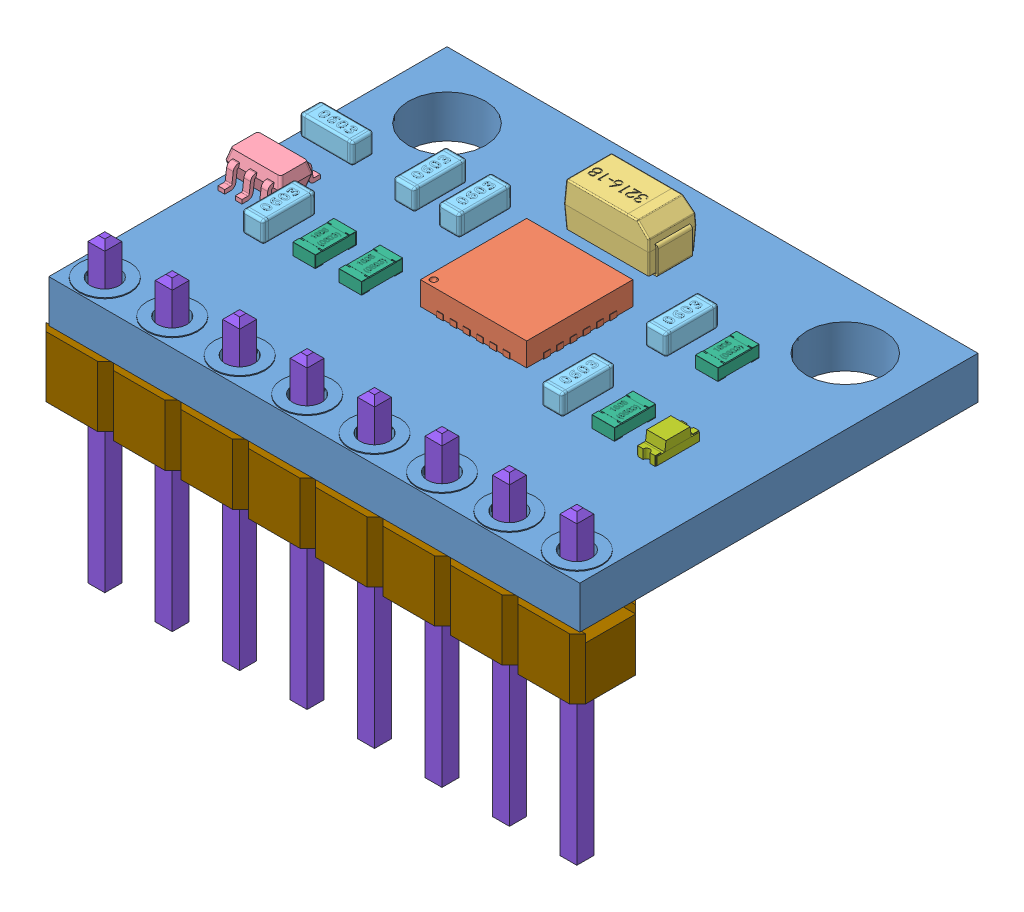
SolidWorks assembly User Library-GY-521, configuration Valor predeterminado. Lengths in mm.
Overall size (20.32 11.82 15.24).
18 component instances, 9 part files, 44 mates.
Components (placement in the parent):
- User Library-GY-521_placa-1: User Library-GY-521_placa [Valor predeterminado] at (0.5666 -1.5108 20) size (20 1.67 15)
- User Library-GY-521_User Library-mpu-6050_qfn-24-1: User Library-GY-521_User Library-mpu-6050_qfn-24 [Default] at (-1.4334 0.1092 17.5) x (0 0 1) z (-1 0 0) size (4.04 0.9 4.04)
- User Library-GY-521_User Library-CAP_TANT_3216-18_A_case-1-1: User Library-GY-521_User Library-CAP_TANT_3216-18_A_case-1 [Default] at (0.3666 0.0692 15.4) x (-1 0 0) z (0 0 -1) size (3.4 1.7 1.8)
- User Library-GY-521_User Library-sot353-1: User Library-GY-521_User Library-sot353 [По умолчанию] at (-8.2834 0.0892 20.35) x (-1 0 0) z (0 1 0) size (2.1 2.3 1)
- User Library-GY-521_User Library-0603(1608M) Cap-1: User Library-GY-521_User Library-0603(1608M) Cap [Default] at (4.4603 0.0892 17.5499) x (0 0 -1) z (1 0 0) size (2.01 0.8 0.79)
- User Library-GY-521_User Library-0603(1608M) Cap-2: User Library-GY-521_User Library-0603(1608M) Cap [Default] at (4.4603 0.0892 21.4501) x (0 0 -1) z (1 0 0) size (2.01 0.8 0.79)
- User Library-GY-521_User Library-RESC1608X05N-1: User Library-GY-521_User Library-RESC1608X05N [Default] at (6.174 0.0892 17.5499) x (0 0 -1) z (0 1 0) size (1.55 0.85 0.45)
- User Library-GY-521_User Library-RESC1608X05N-2: User Library-GY-521_User Library-RESC1608X05N [Default] at (6.174 0.0892 21.4501) x (0 0 -1) z (0 1 0) size (1.55 0.85 0.45)
- User Library-GY-521_User Library-LED SMD0603-1: User Library-GY-521_User Library-LED SMD0603 [Default] at (7.8618 0.0844 20.8327) x (1 0 0) z (0 1 0) size (0.73 1.65 0.68)
- User Library-GY-521_User Library-RESC1608X05N-3: User Library-GY-521_User Library-RESC1608X05N [Default] at (-3.3534 0.0892 21.4501) x (0 0 -1) z (0 1 0) size (1.55 0.85 0.45)
- User Library-GY-521_User Library-RESC1608X05N-4: User Library-GY-521_User Library-RESC1608X05N [Default] at (-5.0934 0.0892 21.4501) x (0 0 -1) z (0 1 0) size (1.55 0.85 0.45)
- User Library-GY-521_User Library-0603(1608M) Cap-3: User Library-GY-521_User Library-0603(1608M) Cap [Default] at (-6.8071 0.0892 21.4501) x (0 0 -1) z (1 0 0) size (2.01 0.8 0.79)
- User Library-GY-521_User Library-0603(1608M) Cap-4: User Library-GY-521_User Library-0603(1608M) Cap [Default] at (-8.2834 0.0892 17.8063) size (2.01 0.8 0.79)
- User Library-GY-521_User Library-0603(1608M) Cap-5: User Library-GY-521_User Library-0603(1608M) Cap [Default] at (-5.0145 0.0892 17.5499) x (0 0 -1) z (1 0 0) size (2.01 0.8 0.79)
- User Library-GY-521_User Library-0603(1608M) Cap-6: User Library-GY-521_User Library-0603(1608M) Cap [Default] at (-3.3271 0.0892 17.5499) x (0 0 -1) z (1 0 0) size (2.01 0.8 0.79)
- User Library-GY-521_User Library-Header_Male_8Pin-1: User Library-GY-521_User Library-Header_Male_8Pin [Default] at (-8.3234 -1.5108 26.5) x (1 0 0) z (0 -1 0) size (20.32 2.49 11.54)
  - User Library-GY-521_User Library-Header_Male_8Pin_PinArray-1: User Library-GY-521_User Library-Header_Male_8Pin_PinArray [Default] at origin size (18.42 0.64 11.54)
  - User Library-GY-521_User Library-Header_Male_8Pin_BodyArray-1: User Library-GY-521_User Library-Header_Male_8Pin_BodyArray [Default] at origin size (20.32 2.49 2.29)
Mates (geometry in assembly coordinates):
- Coincidente2: coincident anti-aligned: plane of User Library-GY-521_placa-1 through (0.5666 0.0892 20) normal (0 1 0); plane of User Library-GY-521_User Library-mpu-6050_qfn-24-1 through (2.6674 0.0892 17.3992) normal (0 -1 0)
- Distância1: distance = 6 mm aligned: plane of User Library-GY-521_User Library-mpu-6050_qfn-24-1 through (-1.5134 0.0916 21.5) normal (0 0 1); plane of User Library-GY-521_placa-1 through (-9.4334 0.0892 27.5) normal (0 0 1)
- Largura1: width anti-aligned: plane of User Library-GY-521_User Library-mpu-6050_qfn-24-1 through (2.5666 0.0916 21.58) normal (1 0 0); plane of User Library-GY-521_placa-1 through (-1.4334 0.0916 17.42) normal (-1 0 0); plane of User Library-GY-521_User Library-mpu-6050_qfn-24-1 through (-9.4334 0.0892 12.5) normal (-1 0 0); plane of User Library-GY-521_placa-1 through (10.5666 0.0892 12.5) normal (1 0 0)
- Coincidente4: coincident anti-aligned: plane of User Library-GY-521_placa-1 through (0.5666 0.0892 20) normal (0 1 0); plane of User Library-GY-521_User Library-CAP_TANT_3216-18_A_case-1-1 through (0.9166 0.0892 14.75) normal (0 -1 0)
- Distância2: distance = 8.5 mm aligned: plane of User Library-GY-521_User Library-CAP_TANT_3216-18_A_case-1-1 through (2.0666 0.1892 14.75) normal (1 0 0); plane of User Library-GY-521_placa-1 through (10.5666 0.0892 12.5) normal (1 0 0)
- Coincidente9: coincident anti-aligned: plane of User Library-GY-521_placa-1 through (0.5666 0.0892 20) normal (0 1 0); plane of User Library-GY-521_User Library-sot353-1 through (-8.1584 0.0892 21.5) normal (0 -1 0)
- Distância5: distance = 6.7 mm aligned: plane of User Library-GY-521_User Library-sot353-1 through (-7.5084 -1.5589 19.2) normal (0 0 -1); plane of User Library-GY-521_placa-1 through (-9.4334 0.0892 12.5) normal (0 0 -1)
- Distância6: distance = 0.1 mm: line of User Library-GY-521_User Library-sot353-1 through (-9.3334 0.6892 19.8216) axis (0 0 1); plane of User Library-GY-521_placa-1 through (-9.4334 0.0892 12.5) normal (-1 0 0)
- Coincidente13: coincident anti-aligned: plane of User Library-GY-521_placa-1 through (0.5666 0.0892 20) normal (0 1 0); plane of User Library-GY-521_User Library-0603(1608M) Cap-1 through (4.854 0.0892 16.7498) normal (0 -1 0)
- Coincidente14: coincident anti-aligned: plane of User Library-GY-521_placa-1 through (0.5666 0.0892 20) normal (0 1 0); plane of User Library-GY-521_User Library-0603(1608M) Cap-2 through (4.854 0.0892 20.65) normal (0 -1 0)
- Coincidente15: coincident anti-aligned: plane of User Library-GY-521_placa-1 through (0.5666 0.0892 20) normal (0 1 0); plane of User Library-GY-521_User Library-0603(1608M) Cap-6 through (-2.9334 0.0892 16.7498) normal (0 -1 0)
- Coincidente16: coincident anti-aligned: plane of User Library-GY-521_placa-1 through (0.5666 0.0892 20) normal (0 1 0); plane of User Library-GY-521_User Library-0603(1608M) Cap-5 through (-4.6208 0.0892 16.7498) normal (0 -1 0)
- Coincidente17: coincident anti-aligned: plane of User Library-GY-521_placa-1 through (0.5666 0.0892 20) normal (0 1 0); plane of User Library-GY-521_User Library-0603(1608M) Cap-4 through (-7.4833 0.0892 18.2) normal (0 -1 0)
- Coincidente18: coincident anti-aligned: plane of User Library-GY-521_placa-1 through (0.5666 0.0892 20) normal (0 1 0); plane of User Library-GY-521_User Library-0603(1608M) Cap-3 through (-6.4134 0.0892 20.65) normal (0 -1 0)
- Coincidente19: coincident anti-aligned: plane of User Library-GY-521_placa-1 through (0.5666 0.0892 20) normal (0 1 0); plane of User Library-GY-521_User Library-RESC1608X05N-4 through (-4.6684 0.0892 22.0751) normal (0 -1 0)
- Coincidente20: coincident anti-aligned: plane of User Library-GY-521_placa-1 through (0.5666 0.0892 20) normal (0 1 0); plane of User Library-GY-521_User Library-RESC1608X05N-3 through (-2.9284 0.0892 22.0751) normal (0 -1 0)
- Coincidente21: coincident anti-aligned: plane of User Library-GY-521_placa-1 through (0.5666 0.0892 20) normal (0 1 0); plane of User Library-GY-521_User Library-RESC1608X05N-2 through (6.599 0.0892 22.0751) normal (0 -1 0)
- Coincidente22: coincident anti-aligned: plane of User Library-GY-521_placa-1 through (0.5666 0.0892 20) normal (0 1 0); plane of User Library-GY-521_User Library-RESC1608X05N-1 through (6.599 0.0892 18.1749) normal (0 -1 0)
- Coincidente23: coincident anti-aligned: plane of User Library-GY-521_placa-1 through (0.5666 0.0892 20) normal (0 1 0); plane of User Library-GY-521_User Library-LED SMD0603-1 through (7.8565 0.0892 22.1999) normal (0 -1 0)
- Distância7: distance = 1.9 mm anti-aligned: plane of User Library-GY-521_User Library-0603(1608M) Cap-2 through (4.0666 0.0892 20.45) normal (0 0 -1); plane of User Library-GY-521_User Library-0603(1608M) Cap-1 through (4.854 0.8766 18.55) normal (0 0 1)
- Coincidente25: coincident aligned: plane of User Library-GY-521_User Library-0603(1608M) Cap-1 through (4.854 0.8766 18.35) normal (1 0 0); plane of User Library-GY-521_User Library-0603(1608M) Cap-2 through (4.854 0.8766 22.2502) normal (1 0 0)
- Distância8: distance = 1.5 mm anti-aligned: plane of User Library-GY-521_User Library-0603(1608M) Cap-1 through (4.0666 0.8766 18.35) normal (-1 0 0); plane of User Library-GY-521_User Library-mpu-6050_qfn-24-1 through (2.5666 0.0916 21.58) normal (1 0 0)
- Largura2: width anti-aligned: plane of User Library-GY-521_User Library-mpu-6050_qfn-24-1 through (-1.5134 0.0916 21.5) normal (0 0 1); plane of User Library-GY-521_User Library-0603(1608M) Cap-1 through (2.6466 0.0916 17.5) normal (0 0 -1); plane of User Library-GY-521_User Library-mpu-6050_qfn-24-1 through (4.0666 0.0892 16.5497) normal (0 0 -1); plane of User Library-GY-521_User Library-0603(1608M) Cap-2 through (4.854 0.8766 22.4503) normal (0 0 1)
- Distância9: distance = 0.9 mm anti-aligned: plane of User Library-GY-521_User Library-RESC1608X05N-2 through (5.754 0.3142 21.4501) normal (-1 0 0); plane of User Library-GY-521_User Library-0603(1608M) Cap-2 through (4.854 0.8766 22.2502) normal (1 0 0)
- Largura3: width anti-aligned: plane of User Library-GY-521_User Library-RESC1608X05N-2 through (6.599 0.3142 22.2251) normal (0 0 1); plane of User Library-GY-521_User Library-0603(1608M) Cap-2 through (6.599 0.3142 20.6751) normal (0 0 -1); plane of User Library-GY-521_User Library-RESC1608X05N-2 through (4.0666 0.0892 20.45) normal (0 0 -1); plane of User Library-GY-521_User Library-0603(1608M) Cap-2 through (4.854 0.8766 22.4503) normal (0 0 1)
- Distância10: distance = 0.9 mm anti-aligned: plane of User Library-GY-521_User Library-LED SMD0603-1 through (7.494 0.1142 20.6501) normal (-1 0 0); plane of User Library-GY-521_User Library-RESC1608X05N-2 through (6.594 0.3142 21.4501) normal (1 0 0)
- Largura4: width anti-aligned: plane of User Library-GY-521_User Library-LED SMD0603-1 through (8.0065 0.0892 22.2751) normal (0 0 1); plane of User Library-GY-521_User Library-RESC1608X05N-2 through (8.0065 0.0892 20.6251) normal (0 0 -1); plane of User Library-GY-521_User Library-LED SMD0603-1 through (6.599 0.3142 20.6751) normal (0 0 -1); plane of User Library-GY-521_User Library-RESC1608X05N-2 through (6.599 0.3142 22.2251) normal (0 0 1)
- Distância11: distance = 0.9 mm anti-aligned: plane of User Library-GY-521_User Library-RESC1608X05N-1 through (5.754 0.3142 17.5499) normal (-1 0 0); plane of User Library-GY-521_User Library-0603(1608M) Cap-1 through (4.854 0.8766 18.35) normal (1 0 0)
- Largura5: width anti-aligned: plane of User Library-GY-521_User Library-0603(1608M) Cap-1 through (4.0666 0.0892 16.5497) normal (0 0 -1); plane of User Library-GY-521_User Library-RESC1608X05N-1 through (4.854 0.8766 18.55) normal (0 0 1); plane of User Library-GY-521_User Library-0603(1608M) Cap-1 through (6.599 0.3142 18.3249) normal (0 0 1); plane of User Library-GY-521_User Library-RESC1608X05N-1 through (6.599 0.3142 16.7749) normal (0 0 -1)
- Distância12: distance = 1.5 mm anti-aligned: plane of User Library-GY-521_User Library-RESC1608X05N-3 through (-2.9334 0.3142 21.4501) normal (1 0 0); plane of User Library-GY-521_User Library-mpu-6050_qfn-24-1 through (-1.4334 0.0916 17.42) normal (-1 0 0)
- Coincidente28: coincident aligned: plane of User Library-GY-521_User Library-RESC1608X05N-2 through (6.599 0.3142 22.2251) normal (0 0 1); plane of User Library-GY-521_User Library-RESC1608X05N-3 through (-2.9284 0.3142 22.2251) normal (0 0 1)
- Coincidente29: coincident aligned: plane of User Library-GY-521_User Library-RESC1608X05N-3 through (-2.9284 0.3142 20.6751) normal (0 0 -1); plane of User Library-GY-521_User Library-RESC1608X05N-4 through (-4.6684 0.3142 20.6751) normal (0 0 -1)
- Distância13: distance = 0.9 mm anti-aligned: plane of User Library-GY-521_User Library-RESC1608X05N-4 through (-4.6734 0.3142 21.4501) normal (1 0 0); plane of User Library-GY-521_User Library-RESC1608X05N-3 through (-3.7734 0.3142 21.4501) normal (-1 0 0)
- Coincidente31: coincident aligned: plane of User Library-GY-521_User Library-0603(1608M) Cap-2 through (4.854 0.8766 22.4503) normal (0 0 1); plane of User Library-GY-521_User Library-0603(1608M) Cap-3 through (-6.4134 0.8766 22.4503) normal (0 0 1)
- Distância14: distance = 0.9 mm anti-aligned: plane of User Library-GY-521_User Library-0603(1608M) Cap-3 through (-6.4134 0.8766 22.2502) normal (1 0 0); plane of User Library-GY-521_User Library-RESC1608X05N-4 through (-5.5134 0.3142 21.4501) normal (-1 0 0)
- Coincidente33: coincident aligned: plane of User Library-GY-521_User Library-0603(1608M) Cap-1 through (4.0666 0.0892 16.5497) normal (0 0 -1); plane of User Library-GY-521_User Library-0603(1608M) Cap-6 through (-3.7208 0.0892 16.5497) normal (0 0 -1)
- Distância15: distance = 1.5 mm anti-aligned: plane of User Library-GY-521_User Library-0603(1608M) Cap-6 through (-2.9334 0.8766 18.35) normal (1 0 0); plane of User Library-GY-521_User Library-mpu-6050_qfn-24-1 through (-1.4334 0.0916 17.42) normal (-1 0 0)
- Coincidente35: coincident aligned: plane of User Library-GY-521_User Library-0603(1608M) Cap-5 through (-5.4082 0.0892 16.5497) normal (0 0 -1); plane of User Library-GY-521_User Library-0603(1608M) Cap-6 through (-3.7208 0.0892 16.5497) normal (0 0 -1)
- Distância16: distance = 0.9 mm anti-aligned: plane of User Library-GY-521_User Library-0603(1608M) Cap-5 through (-4.6208 0.8766 18.35) normal (1 0 0); plane of User Library-GY-521_User Library-0603(1608M) Cap-6 through (-3.7208 0.8766 18.35) normal (-1 0 0)
- Largura6: width anti-aligned: plane of User Library-GY-521_User Library-sot353-1 through (-9.0584 -1.5589 20.35) normal (-1 0 0); plane of User Library-GY-521_User Library-0603(1608M) Cap-4 through (-7.5084 -1.5589 20.35) normal (1 0 0); plane of User Library-GY-521_User Library-sot353-1 through (-7.2833 0.0892 17.4126) normal (1 0 0); plane of User Library-GY-521_User Library-0603(1608M) Cap-4 through (-9.2835 0.8766 18.2) normal (-1 0 0)
- Distância17: distance = 1 mm anti-aligned: plane of User Library-GY-521_User Library-0603(1608M) Cap-4 through (-9.0835 0.8766 18.2) normal (0 0 1); plane of User Library-GY-521_User Library-sot353-1 through (-8.8084 -1.5589 19.2) normal (0 0 -1)
- Coincidente37: coincident anti-aligned: plane of User Library-GY-521_placa-1 through (0.5666 -1.5108 20) normal (0 -1 0); plane of User Library-GY-521_User Library-Header_Male_8Pin-1/User Library-GY-521_User Library-Header_Male_8Pin_BodyArray-1 through (-9.5934 -1.5108 27.745) normal (0 1 0)
- Largura7: width anti-aligned: plane of User Library-GY-521_User Library-Header_Male_8Pin-1/User Library-GY-521_User Library-Header_Male_8Pin_BodyArray-1 through (-9.5934 -1.5108 25.255) normal (-1 0 0); plane of User Library-GY-521_placa-1 through (10.7266 -1.5108 27.745) normal (1 0 0); plane of User Library-GY-521_User Library-Header_Male_8Pin-1/User Library-GY-521_User Library-Header_Male_8Pin_BodyArray-1 through (10.5666 0.0892 12.5) normal (1 0 0); plane of User Library-GY-521_placa-1 through (-9.4334 0.0892 12.5) normal (-1 0 0)
- Distância18: distance = 0.68 mm aligned: plane of User Library-GY-521_placa-1 through (-9.4334 0.0892 27.5) normal (0 0 1); plane of User Library-GY-521_User Library-Header_Male_8Pin-1/User Library-GY-521_User Library-Header_Male_8Pin_PinArray-1 through (-8.6434 1.4892 26.82) normal (0 0 1)
